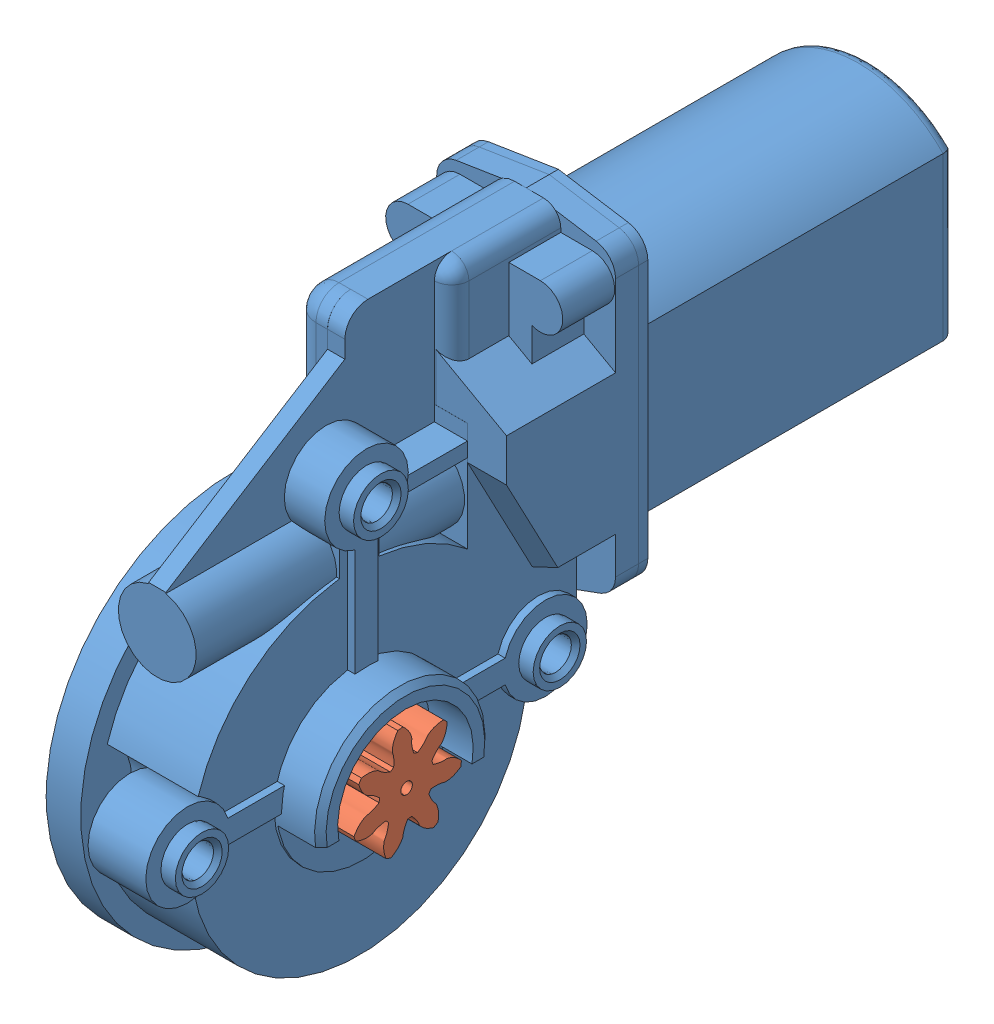
SolidWorks assembly motor, configuration Predeterminado. Lengths in mm.
Overall size (32.52 95.25 141.5).
2 component instances, 2 part files, 2 mates.
Components (placement in the parent):
- motor-1: motor [Predeterminado] at (-11.5992 19.1206 0) size (32.25 95.25 141.5)
- pi±on1-1: pi±on1 [Predeterminado] at (-2.3492 -13.2544 97.25) x (0 0.11389 -0.993493) z (1 0 0) size (18.85 18.38 7.83)
Mates (geometry in assembly coordinates):
- Concéntrica1: concentric anti-aligned: circle of motor-1; circle of pi±on1-1
- Coincidente1: coincident anti-aligned: plane of motor-1 through (-2.3492 -13.2544 97.25) normal (1 0 0); plane of pi±on1-1 through (-2.3492 -13.2544 97.25) normal (-1 0 0)
